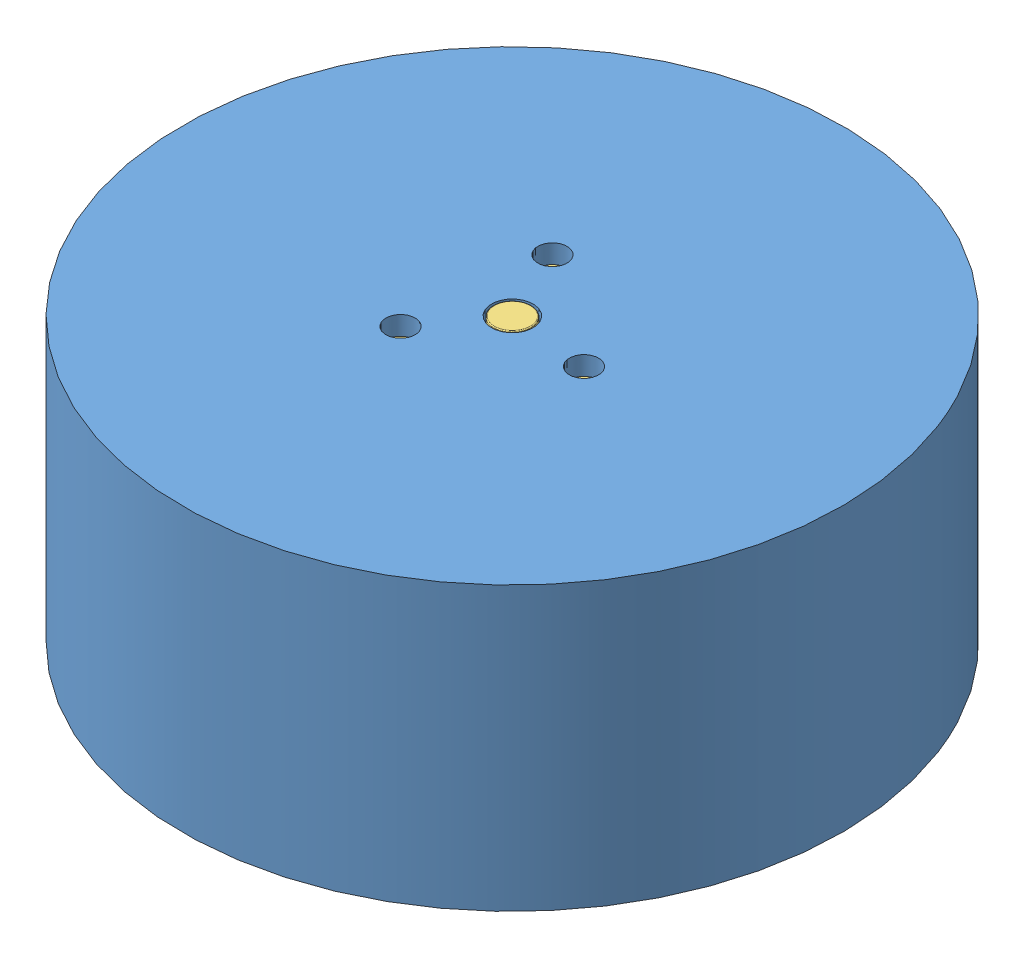
SolidWorks assembly 电机+摩擦轮, configuration 默认. Lengths in mm.
Overall size (92.58 36.7 92.58).
6 component instances, 4 part files, 2 mates.
Components (placement in the parent):
- 摩擦轮-1: 摩擦轮 [默认] at (-0.8607 -14.3749 65.0044) x (-0.410815 0 -0.911719) z (0.911719 0 -0.410815) size (70 30 70)
- 4114电机-1: 4114电机 [默认] at (30.7352 -1.3863 98.4607) x (-0.707718 0 0.706495) z (-0.706495 0 -0.707718) size (46 36.7 46)
  - 4114电机.STEP-1: 4114电机.STEP [默认] at origin size (46 36.7 46)
    - ____3.STEP-1: ____3.STEP [默认] at (-1.2757 -9.9886 46) size (46 16 46)
    - ____2.STEP-1: ____2.STEP [默认] at (-1.2757 15.0114 46) size (46 11 46)
    - ____1.STEP-1: ____1.STEP [默认] at (-1.2757 -17.6886 46) x (-1 0 0) z (0 0 1) size (46 9.7 46)
Mates (geometry in assembly coordinates):
- 同心1: concentric aligned: cylinder of 摩擦轮-1 through (-0.8607 11.6251 65.0044) axis (0 -1 0) radius 23.2; cylinder of 4114电机-1/4114电机.STEP-1/____3.STEP-1 through (-0.8607 4.6251 65.0044) axis (0 -1 0) radius 23
- 重合1: coincident aligned: plane of 摩擦轮-1 through (-0.8607 15.6251 65.0044) normal (0 1 0); plane of 4114电机-1/4114电机.STEP-1/____2.STEP-1 through (-0.8607 15.6251 65.0044) normal (0 1 0)
